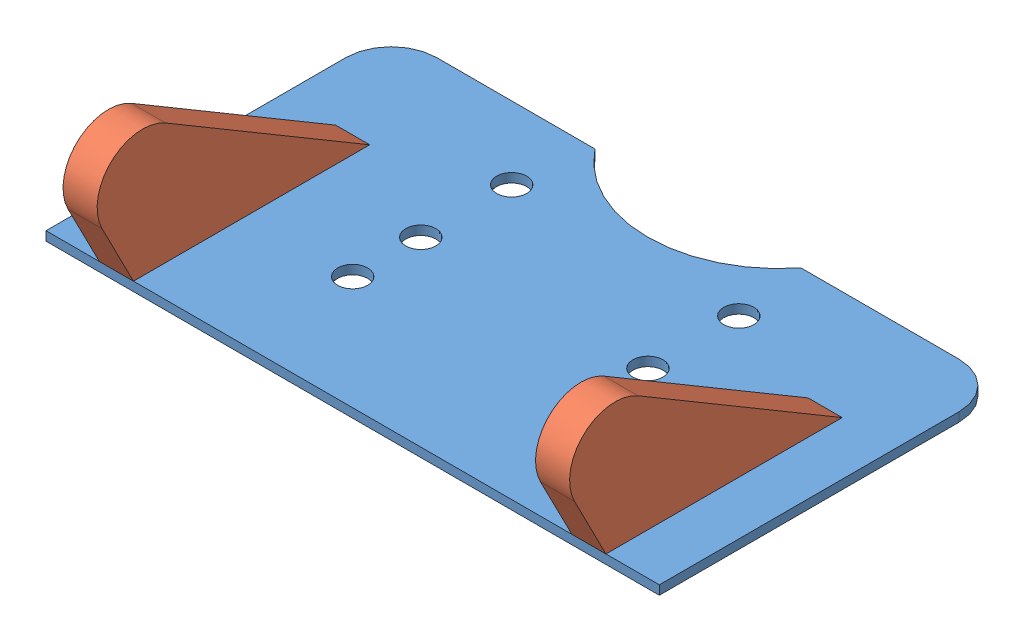
SolidWorks assembly HAULER, BASEPLATE TOP LEVEL, configuration Default. Lengths in mm.
Overall size (85.72 19.05 53.34).
3 component instances, 2 part files, 6 mates.
Components (placement in the parent):
- HAULER, BASEPLATE, FRAME-1: HAULER, BASEPLATE, FRAME [Default] at (0.6543 -3.9124 26.1611) size (85.72 1.27 48.26)
- HAULER, BASEPLATE, PIVOT-1: HAULER, BASEPLATE, PIVOT [Default] at (-34.747 8.7876 24.8911) size (4.76 17.78 38.1)
- HAULER, BASEPLATE, PIVOT-2: HAULER, BASEPLATE, PIVOT [Default] at (31.293 8.7876 24.8911) size (4.76 17.78 38.1)
Mates (geometry in assembly coordinates):
- Coincident1: coincident anti-aligned: plane of HAULER, BASEPLATE, FRAME-1 through (-43.1607 -2.6424 -22.0989) normal (0 1 0); plane of HAULER, BASEPLATE, PIVOT-1 through (-29.9845 -2.6424 26.1611) normal (0 -1 0)
- Coincident2: coincident anti-aligned: plane of HAULER, BASEPLATE, FRAME-1 through (-43.1607 -2.6424 -22.0989) normal (0 1 0); plane of HAULER, BASEPLATE, PIVOT-2 through (36.0555 -2.6424 26.1611) normal (0 -1 0)
- Concentric1: concentric aligned: cylinder of HAULER, BASEPLATE, PIVOT-1 through (-29.9845 8.7876 24.8911) axis (-1 0 0) radius 6.35; cylinder of HAULER, BASEPLATE, PIVOT-2 through (36.0555 8.7876 24.8911) axis (-1 0 0) radius 6.35
- Coincident3: coincident: plane of HAULER, BASEPLATE, FRAME-1 through (44.4693 -2.6424 26.1611) normal (0 0 1); line of HAULER, BASEPLATE, PIVOT-1 through (-29.9845 -2.6424 26.1611) axis (-1 0 0)
- Concentric2: concentric anti-aligned: cone of HAULER, BASEPLATE, FRAME-1 through (-32.3657 -3.9124 21.3986) axis (0 1 0); cylinder of HAULER, BASEPLATE, PIVOT-1 through (-32.3657 -2.6424 21.3986) axis (0 -1 0) radius 1.0922
- Concentric3: concentric anti-aligned: cone of HAULER, BASEPLATE, FRAME-1 through (33.6743 -3.9124 21.3986) axis (0 1 0); cylinder of HAULER, BASEPLATE, PIVOT-2 through (33.6743 -2.6424 21.3986) axis (0 -1 0) radius 1.0922
